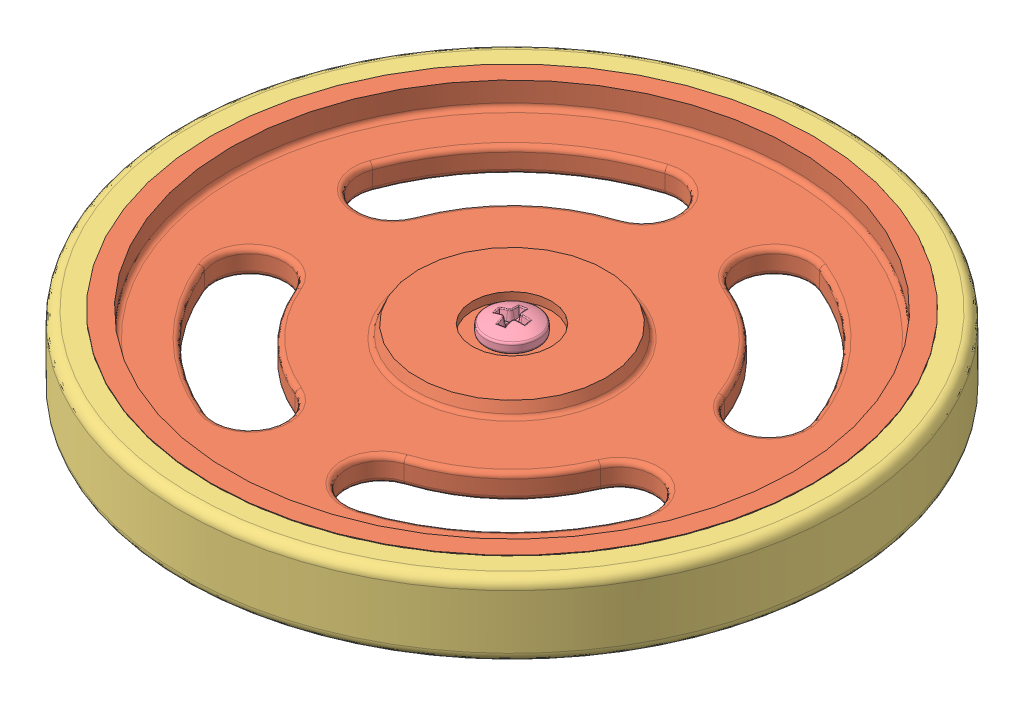
SolidWorks assembly Roda_assembly, configuration Default. Lengths in mm.
Overall size (66.8 12.05 66.8).
5 component instances, 4 part files, 4 mates.
Components (placement in the parent):
- Servo_saida-1: Servo_saida [Default] at (1.1613 -4.0507 2.1392) size (11 8.41 11)
- Roda-1: Roda [Default] at (3.4945 3.6185 3.1113) x (1 0 0) z (0 1 0) size (66.8 66.8 7.56)
  - Roda1-1: Roda1 [Default] at (-2.3333 0.9721 0.5708) size (65 65 7.5)
  - Roda2-1: Roda2 [Default] at (-2.3333 0.9721 0.5708) size (66.8 66.8 7.5)
- Parafuso_Servo-1: Parafuso_Servo [Default] at (1.1613 2.9493 2.1392) x (0 1 0) z (0.175553 0 0.98447) size (9.26 5.35 5.35)
Mates (geometry in assembly coordinates):
- Concentric1: concentric aligned: cylinder of Roda-1/Roda1-1 through (1.1613 -20.8107 2.1392) axis (0 -1 0) radius 1; cylinder of Servo_saida-1 through (1.1613 4.3493 2.1392) axis (0 -1 0) radius 3
- Concentric2: concentric aligned: cylinder of Parafuso_Servo-1 through (1.1613 -1.7007 2.1392) axis (0 -1 0) radius 1; cylinder of Roda-1/Roda1-1 through (1.1613 -20.8107 2.1392) axis (0 -1 0) radius 1
- Coincident1: coincident anti-aligned: plane of Roda-1/Roda1-1 through (1.1613 5.8993 1.1392) normal (0 1 0); plane of Parafuso_Servo-1 through (0.9418 5.8993 0.9086) normal (0 -1 0)
- Coincident2: coincident anti-aligned: plane of Servo_saida-1 through (1.1613 4.3493 2.1392) normal (0 1 0); plane of Roda-1/Roda1-1 through (1.1613 4.3493 -0.6108) normal (0 -1 0)
